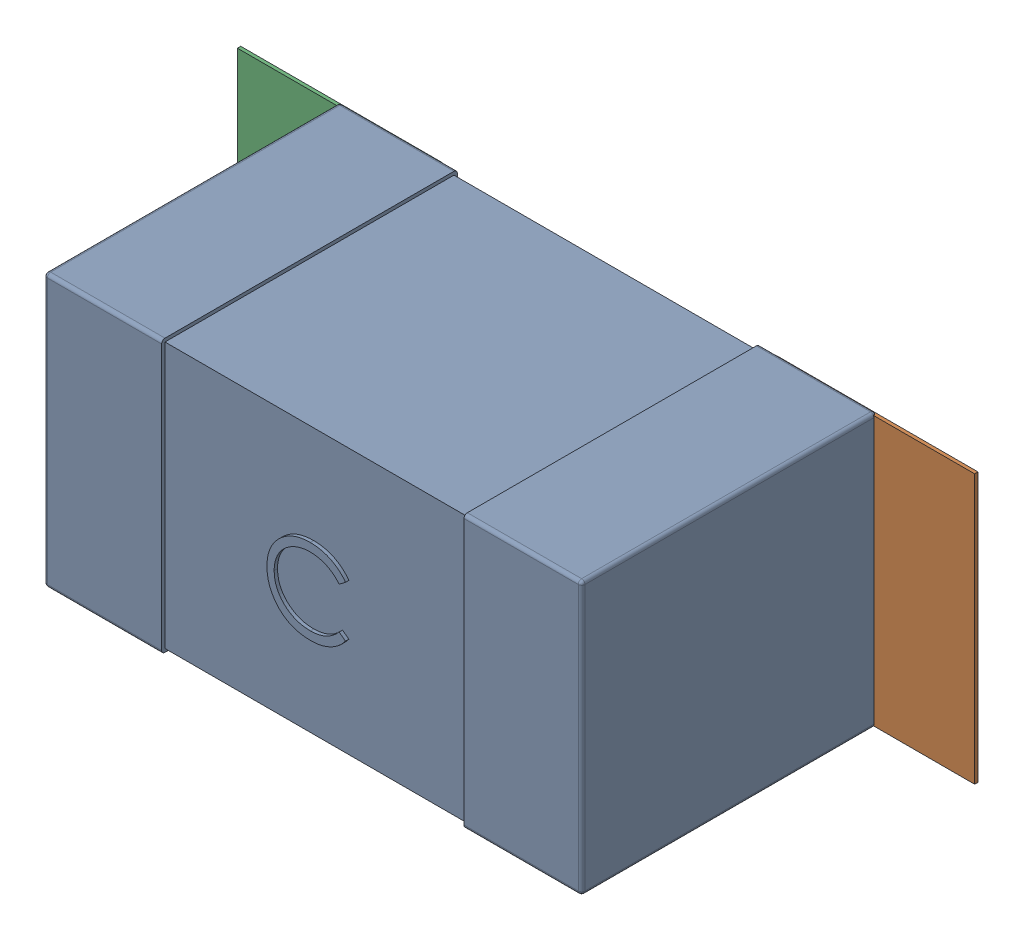
SolidWorks assembly C41, configuration Défaut. Lengths in mm.
Overall size (2.19 0.81 0.88).
5 component instances, 2 part files, 0 mates.
Components (placement in the parent):
- 0603_C-1: 0603_C [Défaut] at (5.392 -12.9414 0) x (1 0 0) z (0 0 1) size (1.6 0.81 0.88)
- 6634915696-1: 6634915696 [Défaut] at (6.642 -12.9414 0) size (0.6 0.8 0.01)
  - Extruded_497-1: Extruded_497 [Défaut] at origin size (0.6 0.8 0.01)
- 6634915696-2: 6634915696 [Défaut] at (5.0471 -12.9414 0) size (0.6 0.8 0.01)
  - Extruded_497-1: Extruded_497 [Défaut] at origin size (0.6 0.8 0.01)
